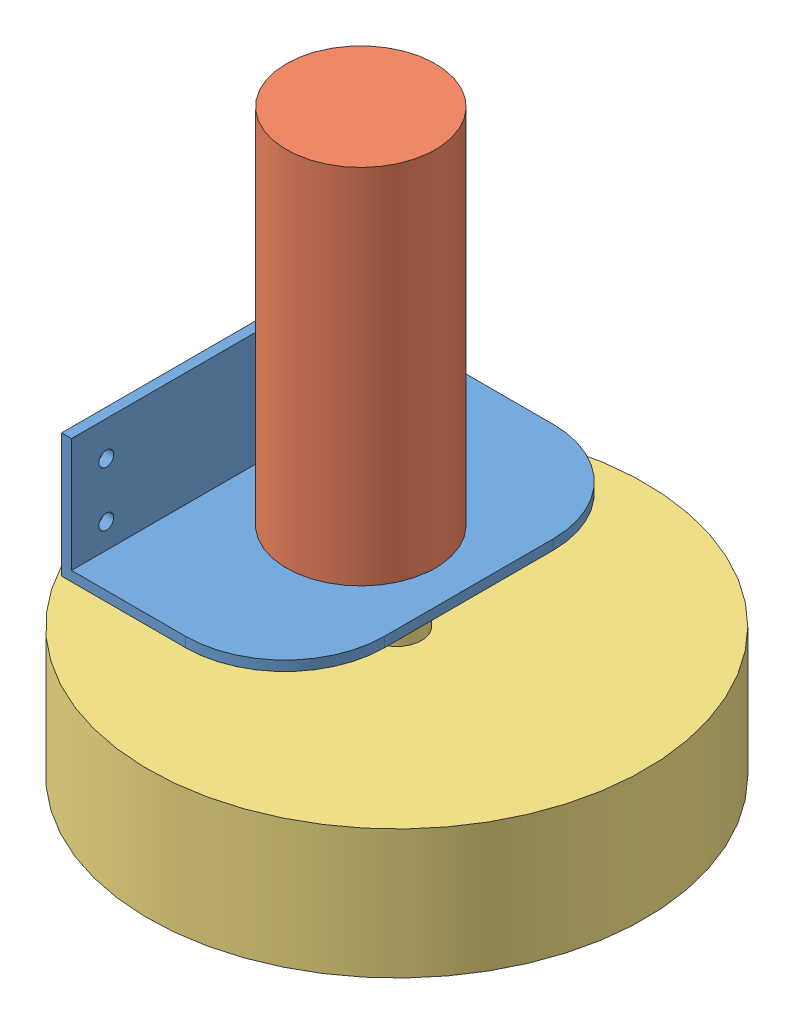
SolidWorks assembly wheel_assy, configuration Default. Lengths in mm.
Overall size (139.95 113 139.95).
3 component instances, 3 part files, 8 mates.
Components (placement in the parent):
- bracket-1: bracket [Default] at (33.8817 26.1088 57.7256) size (45 25 74)
- emd30-1: emd30 [Default] at (26.622 101.1088 57.6925) x (-0.00456 0 0.99999) z (0.99999 0 0.00456) size (30 77 30)
- wheel_to_check_hub_dimensions-1: wheel_to_check_hub_dimensions [Default] at (33.8817 14.1088 57.7256) x (0.598067 0 -0.801446) z (-0.801446 0 -0.598067) size (100 36 100)
Mates (geometry in assembly coordinates):
- Concentric1: concentric: circle of bracket-1; cylinder of emd30-1 through (33.8817 24.1088 57.7256) axis (0 1 0) radius 5
- Coincident2: coincident: plane of bracket-1 through (33.8817 26.1088 57.7256) normal (0 -1 0); plane of emd30-1 through (26.622 26.1088 57.6925) normal (0 -1 0)
- Coincident3: coincident: plane of emd30-1 through (33.8817 24.1088 57.7256) normal (0 -1 0); plane of wheel_to_check_hub_dimensions-1 through (33.8817 24.1088 57.7256) normal (0 1 0)
- Concentric2: concentric: cylinder of emd30-1 through (33.8817 24.1088 57.7256) axis (0 1 0) radius 5; cylinder of wheel_to_check_hub_dimensions-1 through (33.8817 24.1088 57.7256) axis (0 -1 0) radius 5
- Lock1: lock: unknown of bracket-1; unknown of emd30-1
- Concentric3: concentric: circle of ?; cylinder of ? through (19.4635 464.7234 185.6096) axis (0 1 0) radius 5
- Coincident5: coincident: plane of ? through (19.4635 477.2234 185.6096) normal (0 -1 0); plane of ? through (12.2038 477.2234 185.5765) normal (0 -1 0)
- Lock2: lock: unknown of ?; unknown of ?
